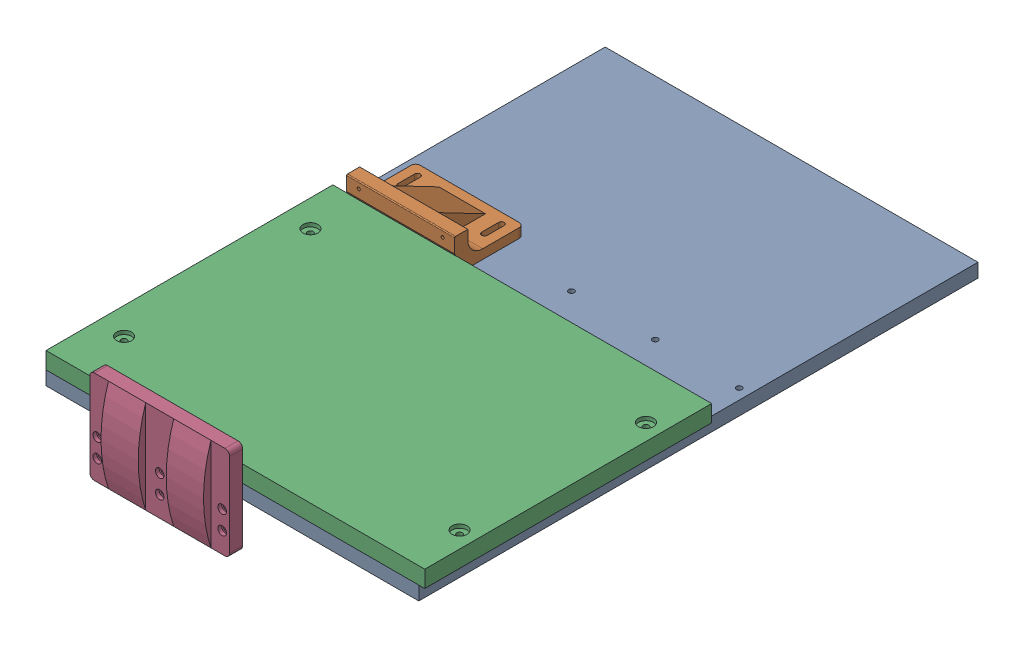
SolidWorks assembly Genmitsu_Work_Area, configuration Default. Lengths in mm.
Overall size (406.4 100 622).
4 component instances, 4 part files, 9 mates.
Components (placement in the parent):
- CNC_Baseplate-1: CNC_Baseplate [Default] at (-320.8345 -68.1364 215.5908) size (400 14.8 600)
- Chessboard_Fixture-1: Chessboard_Fixture [Default] at (-305.0845 -53.3364 -95.2218) size (116 36.05 74)
- Pine_Spoil_Board-1: Pine_Spoil_Board [Default] at (-320.8345 -53.3364 215.5908) size (406.4 18 307.8)
- Front_Stop-1: Front_Stop [Default] at (-259.8156 -116.2864 215.5908) x (1 0 0) z (0 -1 0) size (150 22 100)
Mates (geometry in assembly coordinates):
- Coincident1: coincident anti-aligned: plane of CNC_Baseplate-1 through (-320.8345 -53.3364 215.5908) normal (0 1 0); plane of Chessboard_Fixture-1 through (-305.0845 -53.3364 -95.2218) normal (0 -1 0)
- Concentric2: concentric anti-aligned: cylinder of CNC_Baseplate-1 through (-292.0845 -53.3364 160.5908) axis (0 -1 0) radius 3; cylinder of Pine_Spoil_Board-1 through (-292.0845 -53.3364 160.5908) axis (0 1 0) radius 3
- Concentric3: concentric anti-aligned: cylinder of CNC_Baseplate-1 through (67.9155 -53.3364 160.5908) axis (0 -1 0) radius 3; cylinder of Pine_Spoil_Board-1 through (67.9155 -53.3364 160.5908) axis (0 1 0) radius 3
- Coincident2: coincident anti-aligned: plane of CNC_Baseplate-1 through (-320.8345 -53.3364 215.5908) normal (0 1 0); plane of Pine_Spoil_Board-1 through (-320.8345 -53.3364 215.5908) normal (0 -1 0)
- Distance1: distance = 19.05 mm aligned: plane of Pine_Spoil_Board-1 through (-320.8345 -35.3364 215.5908) normal (0 1 0); plane of Front_Stop-1 through (-259.8156 -16.2864 229.5908) normal (0 1 0)
- Coincident4: coincident anti-aligned: plane of CNC_Baseplate-1 through (-320.8345 -53.3364 215.5908) normal (0 0 1); plane of Front_Stop-1 through (-259.8156 -116.2864 215.5908) normal (0 0 -1)
- Tangent1: tangent anti-aligned: cylinder of CNC_Baseplate-1 through (-292.0845 -53.3364 -139.4092) axis (0 -1 0) radius 3; plane of Chessboard_Fixture-1 through (-295.0845 -53.3364 -154.2218) normal (1 0 0)
- Tangent2: tangent anti-aligned: cylinder of CNC_Baseplate-1 through (-202.0845 -53.3364 -139.4092) axis (0 -1 0) radius 3; plane of Chessboard_Fixture-1 through (-199.0845 -53.3364 -154.2218) normal (-1 0 0)
- LimitDistance1: limit distance = 306.8126 mm anti-aligned: plane of Chessboard_Fixture-1 through (-172.592 -17.2864 -91.2218) normal (0 0 1); plane of Front_Stop-1 through (-259.8156 -116.2864 215.5908) normal (0 0 -1)
